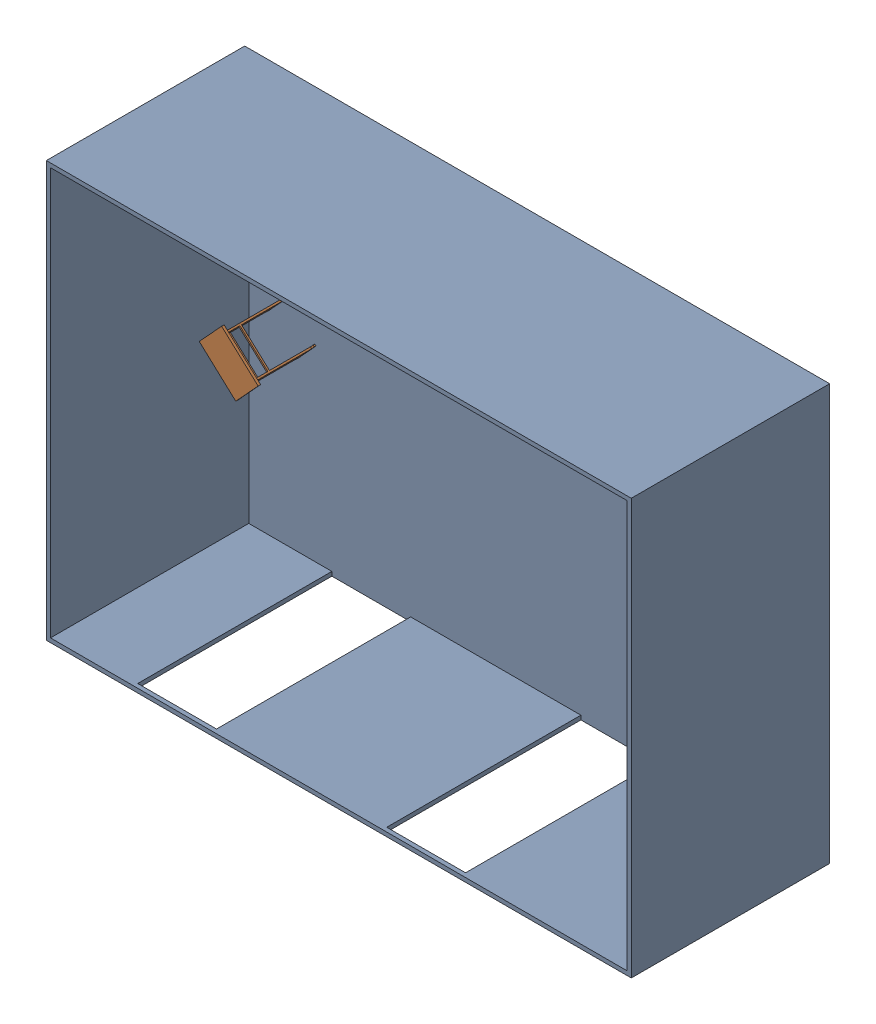
SolidWorks assembly Celda_completa, configuration Predeterminado. Lengths in mm.
Overall size (7080 5029 2401).
5 component instances, 3 part files, 7 mates.
Components (placement in the parent):
- Celda-1: Celda [Predeterminado] at (-5269.1549 -2934.1833 996.2518) size (7080 5029 2401)
- Mesa-1: Mesa [Predeterminado] at (-8237.1549 -3081.2246 1731.2518) x (0.675944 0.736953 0) z (0 0 1) size (400 600 765)
- Zapata-1: Zapata [Predeterminado] at (-7255.1549 -2589.0731 996.2518) x (0 1 0) z (0 0 1) size (170 140 60)
- Zapata-2: Zapata [Predeterminado] at (-7130.1096 -2372.4883 996.2518) x (-0.866025 -0.5 0) z (0 0 1) size (170 140 60)
- Zapata-3: Zapata [Predeterminado] at (-7380.2001 -2372.4883 996.2518) x (0.866025 -0.5 0) z (0 0 1) size (170 140 60)
Mates (geometry in assembly coordinates):
- Coincidente3: coincident anti-aligned: plane of Celda-1 through (-5269.1549 -2934.1833 996.2518) normal (0 0 1); plane of Mesa-1 through (-8237.1549 -3081.2246 996.2518) normal (0 0 -1)
- Distancia3: distance = 690 mm: point of assembly; line of assembly; point of Mesa-1
- Distancia4: distance = 230 mm: point of Mesa-1; line of Celda-1 through (-8759.1549 -469.6833 996.2518) axis (0 -1 0)
- Distancia6: distance = 350 mm: point of assembly; line of assembly; point of Mesa-1
- Coincidente8: coincident anti-aligned: plane of Celda-1 through (-5269.1549 -2934.1833 996.2518) normal (0 0 1); plane of Zapata-1 through (-7255.1549 -2589.0731 996.2518) normal (0 0 -1)
- Paralelo1: parallel anti-aligned: plane of Celda-1 through (-8759.1549 -5398.6833 3396.2518) normal (0 1 0); plane of Zapata-1 through (-7325.1549 -2674.0731 1026.2518) normal (0 -1 0)
- Coincidente18: coincident: moEndPointRef_w of Zapata-1
